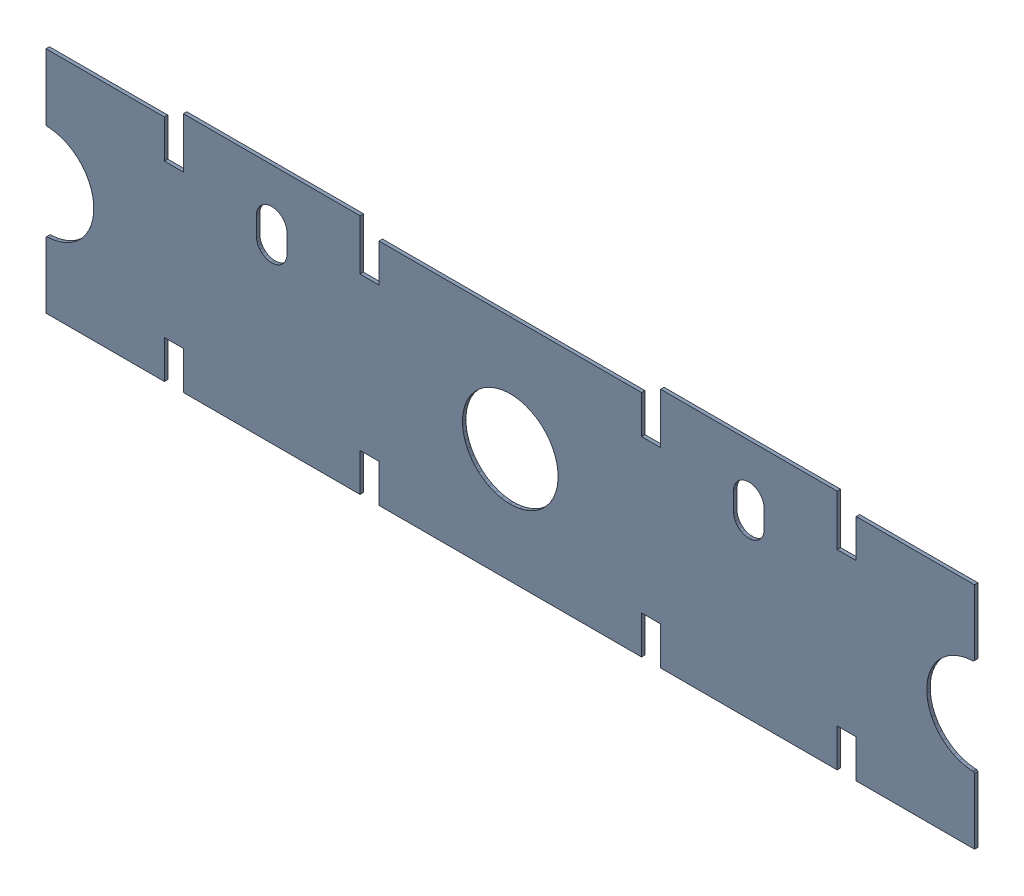
SolidWorks assembly Polygon Not Repour After Edit  (Top Layer-No Net) on Top Layer-1, configuration По умолчанию. Lengths in mm.
Overall size (97.3 25.3 0.36).
2 component instances, 1 part files, 0 mates.
Components (placement in the parent):
- Polygon Region (3 hole(s)) Top Layer-1-1: Polygon Region (3 hole(s)) Top Layer-1 [По умолчанию] at (0 0 -0.3702) size (97.3 25.3 0.36)
  - Polygon Region (3 hole(s)) Top Layer-Part-1-1-1: Polygon Region (3 hole(s)) Top Layer-Part-1-1 [По умолчанию] at origin size (97.3 25.3 0.36)
